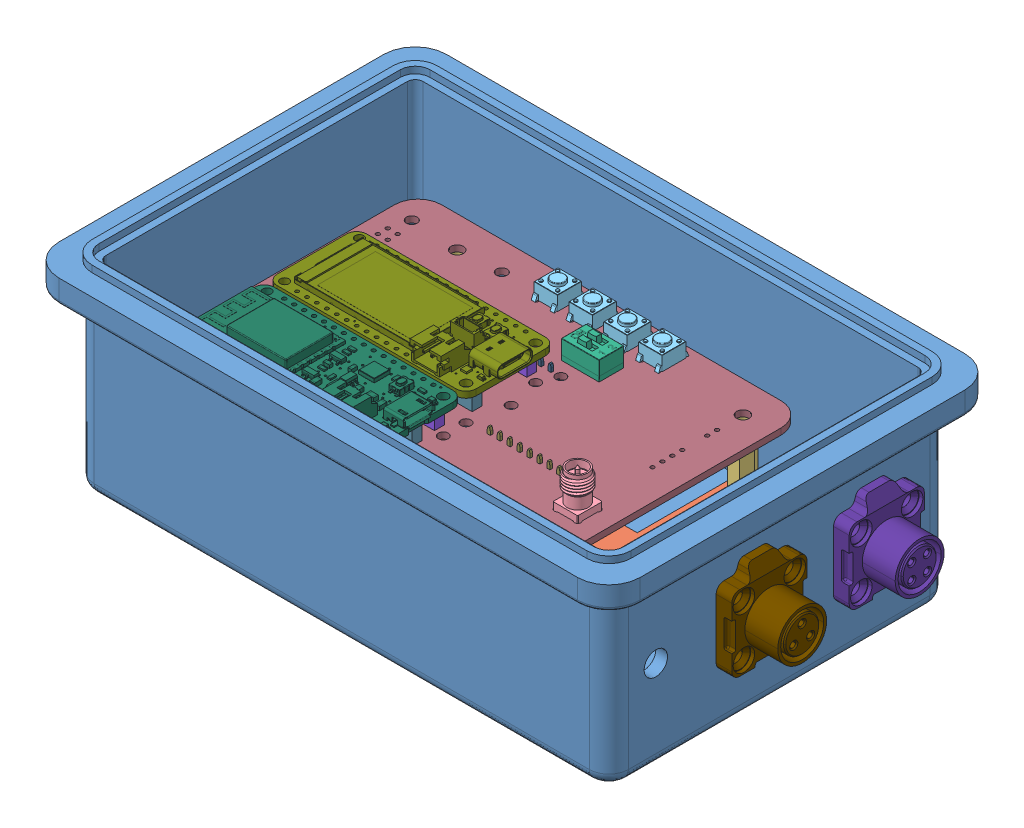
SolidWorks assembly Box_Assembly, configuration Default. Lengths in mm.
Overall size (154.9 51.7 99).
39 component instances, 19 part files, 26 mates.
Components (placement in the parent):
- Box_Bottom-1: Box_Bottom [Default] at origin size (148.5 51.7 99)
- Box_Lid-1: Box_Lid [Default] at (0 56 0) size (148.5 20 99) (hidden)
- PCB_Holder-1: PCB_Holder [Default] at (68.25 9.5 -43.5) size (110 3.5 64)
- 15mm Standoff-1: 15mm Standoff [Default] at (99.25 13 -15.5) size (5.77 15 5.09)
- 15mm Standoff-2: 15mm Standoff [Default] at (99.25 13 -71.5) size (5.77 15 5.09)
- 15mm Standoff-3: 15mm Standoff [Default] at (26.25 13 -15.5) size (5.77 15 5.09)
- 15mm Standoff-4: 15mm Standoff [Default] at (26.25 13 -71.5) size (5.77 15 5.09)
- PCB_Assembly-4: PCB_Assembly [Default] at (-13.75 28 21.5) x (0 0 -1) z (0 1 0) size (72 98.76 19.87)
  - CONSMA001-ND-1: CONSMA001-ND [По умолчанию] at (51 -112.776 -2.5) x (1 0 0) z (0 -1 0) size (6.54 13.8 7.33)
  - Tactal Switch -Thru (6mmx 6mmx4.5mm)-1: Tactal Switch -Thru (6mmx 6mmx4.5mm) [Default] at (95.2393 -90.1528 1.6) size (8.37 5.99 7.62)
  - Tactal Switch -Thru (6mmx 6mmx4.5mm)-2: Tactal Switch -Thru (6mmx 6mmx4.5mm) [Default] at (95.2393 -81.2584 1.6) size (8.37 5.99 7.62)
  - Tactal Switch -Thru (6mmx 6mmx4.5mm)-3: Tactal Switch -Thru (6mmx 6mmx4.5mm) [Default] at (95.2393 -72.364 1.6) size (8.37 5.99 7.62)
  - Tactal Switch -Thru (6mmx 6mmx4.5mm)-4: Tactal Switch -Thru (6mmx 6mmx4.5mm) [Default] at (95.2393 -63.4696 1.6) size (8.37 5.99 7.62)
  - SW-NDS-02V.stp-1: SW-NDS-02V.stp [Default] at (85.025 -82.574 1.219) size (6.35 9.65 8.88)
  - 12-Pin Header - Female - 2.54mm.step-1: 12-Pin Header - Female - 2.54mm.step [Default] at (31 -65.41 1.3) x (0 1 0) z (1 0 0) size (30.98 8 2.5)
    - 12er Pin Header Female.step-1: 12er Pin Header Female.step [Default] at (24.13 0 0) size (30.98 8 2.5)
  - 16-Pin Header - Female - 2.54mm.step-1: 16-Pin Header - Female - 2.54mm.step [Default] at (51.35 -75.57 1.3) x (0 1 0) z (1 0 0) size (41.14 8 2.5)
    - 16er Pin Header Female.step-1: 16er Pin Header Female.step [Default] at (24.13 0 0) size (41.14 8 2.5)
  - 12-Pin Header - Female - 2.54mm.step-2: 12-Pin Header - Female - 2.54mm.step [Default] at (54.65 -65.41 1.3) x (0 1 0) z (1 0 0) size (30.98 8 2.5)
    - 12er Pin Header Female.step-1: 12er Pin Header Female.step [Default] at (24.13 0 0) size (30.98 8 2.5)
  - 16-Pin Header - Female - 2.54mm.step-2: 16-Pin Header - Female - 2.54mm.step [Default] at (74.95 -75.57 1.3) x (0 1 0) z (1 0 0) size (41.14 8 2.5)
    - 16er Pin Header Female.step-1: 16er Pin Header Female.step [Default] at (24.13 0 0) size (41.14 8 2.5)
  - 8-Pin Header - Female - 2.54mm.step-1: 8-Pin Header - Female - 2.54mm.step [Default] at (78.45 -36.22 0.3) x (0 -1 0) z (1 0 0) size (20.82 8 2.5)
    - 8er Pin Header Female.step-1: 8er Pin Header Female.step [Default] at (24.13 0 0) size (20.82 8 2.5)
  - 7-Pin Header - Female - 2.54mm.step-1: 7-Pin Header - Female - 2.54mm.step [Default] at (78.2 -78.73 0.3) x (0 1 0) z (-1 0 0) size (18.28 8 2.5)
    - 7er Pin Header Female.step-1: 7er Pin Header Female.step [Default] at (24.13 0 0) size (18.28 8 2.5)
  - 5-Pin Header - Female - 2.54mm.step-1: 5-Pin Header - Female - 2.54mm.step [Default] at (31.1 -95.03 0.3) x (0 1 0) z (-1 0 0) size (13.2 8 2.5)
    - 5er Pin Header Female.step-1: 5er Pin Header Female.step [Default] at (24.13 0 0) size (13.2 8 2.5)
  - 9-Pin Header - Female - 2.54mm.step-1: 9-Pin Header - Female - 2.54mm.step [Default] at (56.5 -105.19 0.3) x (0 1 0) z (-1 0 0) size (23.36 8 2.5)
    - 9er Pin Header Female.step-1: 9er Pin Header Female.step [Default] at (24.13 0 0) size (23.36 8 2.5)
  - Pioneer Controller-1: Pioneer Controller [Default] at origin size (72 98.76 1.6)
  - 15-Pin Header - Female - 2.54mm.step-1: 15-Pin Header - Female - 2.54mm.step [Default] at (45.0498 -76.1859 1.3) x (0.000004 1 0) z (1 -0.000004 0) size (38.6 8 2.5)
    - 15er Pin Header Female.step-1: 15er Pin Header Female.step [Default] at (24.13 0 0) size (38.6 8 2.5)
  - 15-Pin Header - Female - 2.54mm.step-2: 15-Pin Header - Female - 2.54mm.step [Default] at (60.3498 -76.186 1.3) x (0.000004 1 0) z (1 -0.000004 0) size (38.6 8 2.5)
    - 15er Pin Header Female.step-1: 15er Pin Header Female.step [Default] at (24.13 0 0) size (38.6 8 2.5)
  - Adafruit ESP8266 Feather-4: Adafruit ESP8266 Feather [Default] at (52.61 -81.915 8.8) x (0 1 0) z (0 0 1) size (51.25 22.86 6.37)
  - ESP32-S2 TFT Feather-1: ESP32-S2 TFT Feather [Default] at (76.2 -31.115 10.37) x (0 -1 0) z (0 0 -1) size (51.88 22.86 8.92)
- Connector Cnlinko LP-12 4 poles-1: Connector Cnlinko LP-12 4 poles [Default] at (136.5 23 -67) x (0 0 -1) z (1 0 0) size (19.2 22.2 22.4)
- Connector Cnlinko LP-12 3 poles-1: Connector Cnlinko LP-12 3 poles [Default] at (136.5 23 -37) x (0 0 -1) z (1 0 0) size (19.2 22.2 22.4)
Mates (geometry in assembly coordinates):
- Coincident1: coincident anti-aligned: plane of Box_Bottom-1 through (5 51.7 0.6) normal (0 0 1); plane of Box_Lid-1 through (131.5 52 0.6) normal (0 0 -1)
- Coincident2: coincident anti-aligned: plane of Box_Bottom-1 through (-0.6 51.7 -82) normal (-1 0 0); plane of Box_Lid-1 through (-0.6 52 -5) normal (1 0 0)
- Coincident4: coincident anti-aligned: plane of Box_Bottom-1 through (0 50 0) normal (0 1 0); plane of Box_Lid-1 through (0 50 0) normal (0 -1 0)
- Coincident5: coincident aligned: cylinder of Box_Bottom-1 through (118.25 5.5 -43.5) axis (0 1 0) radius 2; circle of PCB_Holder-1
- Concentric1: concentric anti-aligned: cylinder of Box_Bottom-1 through (18.25 5.5 -43.5) axis (0 1 0) radius 2; cylinder of PCB_Holder-1 through (18.25 13 -43.5) axis (0 -1 0) radius 2
- Coincident6: coincident anti-aligned: plane of Box_Bottom-1 through (18.25 9.5 -43.5) normal (0 1 0); plane of PCB_Holder-1 through (68.25 9.5 -43.5) normal (0 -1 0)
- Coincident7: coincident anti-aligned: plane of PCB_Holder-1 through (68.25 13 -43.5) normal (0 1 0); plane of 15mm Standoff-1 through (99.25 13 -15.5) normal (0 -1 0)
- Concentric2: concentric aligned: cylinder of PCB_Holder-1 through (99.25 13 -15.5) axis (0 -1 0) radius 1.6; cylinder of 15mm Standoff-1 through (99.25 28 -15.5) axis (0 -1 0) radius 1.6
- Coincident8: coincident anti-aligned: plane of PCB_Holder-1 through (68.25 13 -43.5) normal (0 1 0); plane of 15mm Standoff-2 through (99.25 13 -71.5) normal (0 -1 0)
- Concentric3: concentric aligned: cylinder of PCB_Holder-1 through (99.25 13 -71.5) axis (0 -1 0) radius 1.6; cylinder of 15mm Standoff-2 through (99.25 28 -71.5) axis (0 -1 0) radius 1.6
- Coincident9: coincident anti-aligned: plane of PCB_Holder-1 through (68.25 13 -43.5) normal (0 1 0); plane of 15mm Standoff-4 through (26.25 13 -71.5) normal (0 -1 0)
- Concentric4: concentric aligned: cylinder of PCB_Holder-1 through (26.25 13 -71.5) axis (0 -1 0) radius 1.6; cylinder of 15mm Standoff-4 through (26.25 28 -71.5) axis (0 -1 0) radius 1.6
- Coincident10: coincident anti-aligned: plane of PCB_Holder-1 through (68.25 13 -43.5) normal (0 1 0); plane of 15mm Standoff-3 through (26.25 13 -15.5) normal (0 -1 0)
- Concentric5: concentric aligned: cylinder of PCB_Holder-1 through (26.25 13 -15.5) axis (0 -1 0) radius 1.6; cylinder of 15mm Standoff-3 through (26.25 28 -15.5) axis (0 -1 0) radius 1.6
- Concentric10: concentric anti-aligned: cylinder of 15mm Standoff-4 through (26.25 28 -71.5) axis (0 -1 0) radius 1.6; cylinder of PCB_Assembly-4/Board-2/Pioneer Controller.step-1/Pioneer Controller PCB.step-1 through (26.25 27.2 -71.5) axis (0 1 0) radius 1.6
- Coincident13: coincident anti-aligned: plane of Box_Bottom-1 through (136.5 44 -87) normal (1 0 0); plane of Connector Cnlinko LP-12 4 poles-1 through (136.5 23 -67) normal (-1 0 0)
- Concentric11: concentric aligned: cylinder of Box_Bottom-1 through (126.5 23 -67) axis (1 0 0) radius 5.5; cylinder of Connector Cnlinko LP-12 4 poles-1 through (128.1 23 -67) axis (1 0 0) radius 5.5
- Coincident14: coincident anti-aligned: plane of Box_Bottom-1 through (136.5 44 -87) normal (1 0 0); plane of Connector Cnlinko LP-12 3 poles-1 through (136.5 23 -37) normal (-1 0 0)
- Concentric13: concentric aligned: cylinder of Box_Bottom-1 through (126.5 23 -37) axis (1 0 0) radius 5.5; cylinder of Connector Cnlinko LP-12 3 poles-1 through (128.1 23 -37) axis (1 0 0) radius 5.5
- Concentric14: concentric aligned: cylinder of PCB_Holder-1 through (99.25 13 -15.5) axis (0 -1 0) radius 1.6; cylinder of 15mm Standoff-1 through (99.25 28 -15.5) axis (0 -1 0) radius 1.6
- Concentric15: concentric aligned: cylinder of PCB_Holder-1 through (99.25 13 -71.5) axis (0 -1 0) radius 1.6; cylinder of 15mm Standoff-2 through (99.25 28 -71.5) axis (0 -1 0) radius 1.6
- Concentric16: concentric anti-aligned: cylinder of 15mm Standoff-1 through (99.25 28 -15.5) axis (0 -1 0) radius 1.6; cylinder of PCB_Assembly-4/Pioneer Controller-1 through (99.25 27.2 -15.5) axis (0 1 0) radius 1.6
- Concentric17: concentric anti-aligned: cylinder of 15mm Standoff-2 through (99.25 28 -71.5) axis (0 -1 0) radius 1.6; cylinder of PCB_Assembly-4/Pioneer Controller-1 through (99.25 27.2 -71.5) axis (0 1 0) radius 1.6
- Coincident15: coincident anti-aligned: plane of 15mm Standoff-1 through (99.25 28 -15.5) normal (0 1 0); plane of PCB_Assembly-4/Pioneer Controller-1 through (57.6287 28 -43.4999) normal (0 -1 0)
- Concentric18: concentric anti-aligned: cylinder of 15mm Standoff-3 through (26.25 28 -15.5) axis (0 -1 0) radius 1.6; cylinder of PCB_Assembly-4/Pioneer Controller-1 through (26.25 27.2 -15.5) axis (0 1 0) radius 1.6
- Coincident16: coincident anti-aligned: cylinder of 15mm Standoff-4 through (26.25 28 -71.5) axis (0 -1 0) radius 1.6; circle of PCB_Assembly-4/Pioneer Controller-1
